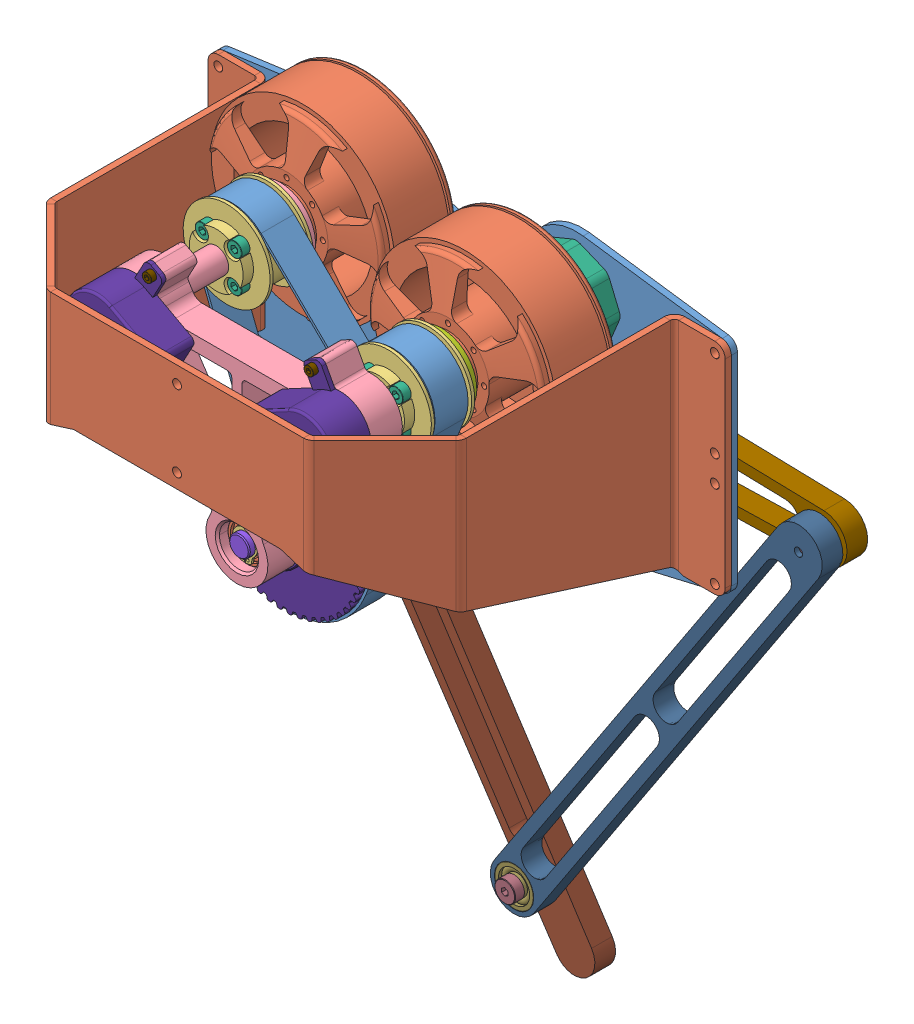
SolidWorks assembly Assembly, configuration Default. Lengths in mm.
Overall size (312.75 390.32 189.52).
164 component instances, 38 part files, 113 mates.
Components (placement in the parent):
- Mounting Plate-1: Mounting Plate [Default] at (803.8236 318.9692 0) size (250 143.05 3)
- Long Motor Assembly-1: Long Motor Assembly [Default] at (703.2032 181.8732 -91.3778) size (125.3 125.3 113)
  - T-Motor U10 KV80-1: T-Motor U10 KV80 [Default] at (50.6204 137.0959 94.3778) x (0.707107 -0.707107 0) z (0 0 1) size (88.6 88.6 43)
  - Timing Belt Pulley-1: Timing Belt Pulley [Default] at (50.6204 137.0959 142.3778) x (-0.707107 0.707107 0) z (0 0 -1) size (42 42 26)
  - Motor Shaft Long-1: Motor Shaft Long [Default] at (50.6204 137.0959 137.3778) x (0 -1 0) z (0 0 1) size (34 34 90)
  - ISO 10642 - M4 x 12 - 12C-9: ISO 10642 - M4 x 12 - 12C [ISO 10642 - M4 x 12 - 12C] at (50.6204 148.5959 142.3578) x (0 0 -1) z (0.997572 0.069644 0) size (12 7.53 7.53)
  - ISO 10642 - M4 x 12 - 12C-10: ISO 10642 - M4 x 12 - 12C [ISO 10642 - M4 x 12 - 12C] at (62.1204 137.0959 142.3578) x (0 0 -1) z (1 0 0) size (12 7.53 7.53)
  - ISO 10642 - M4 x 12 - 12C-11: ISO 10642 - M4 x 12 - 12C [ISO 10642 - M4 x 12 - 12C] at (39.1204 137.0959 142.3578) x (0 0 -1) z (1 0 0) size (12 7.53 7.53)
  - ISO 10642 - M4 x 12 - 12C-12: ISO 10642 - M4 x 12 - 12C [ISO 10642 - M4 x 12 - 12C] at (50.6204 125.5959 142.3578) x (0 0 -1) z (1 0 0) size (12 7.53 7.53)
  - ISO 4762 M4 x 25 - 25C-2: ISO 4762 M4 x 25 - 25C [PreviewCfg] at (58.3986 144.8741 167.3778) x (0 0 -1) z (1 0 0) size (29 7 7)
  - ISO 4762 M4 x 25 - 25C-4: ISO 4762 M4 x 25 - 25C [ISO 4762 M4 x 25 - 25C] at (42.8422 144.8741 167.3778) x (0 0 -1) z (0.999681 -0.025261 0) size (29 7 7)
  - ISO 4762 M4 x 25 - 25C-6: ISO 4762 M4 x 25 - 25C [ISO 4762 M4 x 25 - 25C] at (42.8422 129.3178 167.3778) x (0 0 -1) z (1 0 0) size (29 7 7)
  - ISO 4762 M4 x 25 - 25C-8: ISO 4762 M4 x 25 - 25C [ISO 4762 M4 x 25 - 25C] at (58.3986 129.3178 167.3778) x (0 0 -1) z (1 0 0) size (29 7 7)
- Short Motor Assembly-1: Short Motor Assembly [Default] at (703.2032 181.8732 -91.3778) size (125.3 125.3 91)
  - T-Motor U10 KV80-1: T-Motor U10 KV80 [Default] at (150.6204 137.0959 116.3778) x (0.707107 0.707107 0) z (0 0 1) size (88.6 88.6 43)
  - Timing Belt Pulley-1: Timing Belt Pulley [Default] at (150.6204 137.0959 164.3778) x (0.707107 0.707107 0) z (0 0 -1) size (42 42 26)
  - Motor Shaft Short-1: Motor Shaft Short [Default] at (150.6204 137.0959 159.3778) x (0 1 0) z (0 0 1) size (34 34 68)
  - ISO 10642 - M4 x 12 - 12C-9: ISO 10642 - M4 x 12 - 12C [ISO 10642 - M4 x 12 - 12C] at (139.1204 137.0959 164.3578) x (0 0 -1) z (1 -0.000264 0) size (12 7.53 7.53)
  - ISO 10642 - M4 x 12 - 12C-10: ISO 10642 - M4 x 12 - 12C [ISO 10642 - M4 x 12 - 12C] at (150.6204 148.5959 164.3578) x (0 0 -1) z (1 0 0) size (12 7.53 7.53)
  - ISO 10642 - M4 x 12 - 12C-11: ISO 10642 - M4 x 12 - 12C [ISO 10642 - M4 x 12 - 12C] at (162.1204 137.0959 164.3578) x (0 0 -1) z (1 0 0) size (12 7.53 7.53)
  - ISO 4762 M4 x 25 - 25C-2: ISO 4762 M4 x 25 - 25C [PreviewCfg] at (142.8422 144.8741 189.3778) x (0 0 -1) z (1 0 0) size (29 7 7)
  - ISO 4762 M4 x 25 - 25C-4: ISO 4762 M4 x 25 - 25C [ISO 4762 M4 x 25 - 25C] at (158.3986 129.3178 189.3778) x (0 0 -1) z (1 0 0) size (29 7 7)
  - ISO 4762 M4 x 25 - 25C-6: ISO 4762 M4 x 25 - 25C [ISO 4762 M4 x 25 - 25C] at (158.3986 144.8741 189.3778) x (0 0 -1) z (1 0 0) size (29 7 7)
  - ISO 10642 - M4 x 12 - 12C-12: ISO 10642 - M4 x 12 - 12C [ISO 10642 - M4 x 12 - 12C] at (150.6204 125.5959 164.3578) x (0 0 -1) z (1 0 0) size (12 7.53 7.53)
  - ISO 4762 M4 x 25 - 25C-8: ISO 4762 M4 x 25 - 25C [ISO 4762 M4 x 25 - 25C] at (142.8422 129.3178 189.3778) x (0 0 -1) z (1 0 0) size (29 7 7)
- Coaxial Shaft Assembly-1: Coaxial Shaft Assembly [Default] at (709.5255 181.8732 -91.3778) size (109.28 109.28 155)
  - Inner Shaft-1: Inner Shaft [Default] at (94.2981 61.5422 207.3778) x (0 0 -1) z (1 0 0) size (155 12 12)
  - Outer Shaft-1: Outer Shaft [Default] at (94.2981 61.5422 163.3778) x (0 0 -1) z (-1 0 0) size (100.5 20 20)
  - Flange-1: Flange [Default] at (94.2981 61.5422 94.3778) x (-0.866025 0.5 0) z (0 0 1) size (80 80 40)
  - SKF - 61804 - 18,SI,NC,18_68-5: SKF - 61804 - 18,SI,NC,18_68 [SKF - 61804 - 18,SI,NC,18_68] at (94.2981 61.5422 97.8778) x (0 0 1) z (-0.071685 -0.997427 0) size (7 32 32)
  - SKF - 61804 - 18,SI,NC,18_68-6: SKF - 61804 - 18,SI,NC,18_68 [SKF - 61804 - 18,SI,NC,18_68] at (94.2981 61.5422 130.8778) x (0 0 1) z (-1 0 0) size (7 32 32)
  - Circlip DIN 471 - 20 x 1.2-3: Circlip DIN 471 - 20 x 1.2 [Circlip DIN 471 - 20 x 1.2] at (94.2981 61.5422 93.0778) x (-1 0 0) z (0 0 -1) size (22.81 25.6 1.2)
  - HK_1210-1: HK_1210 [Default] at (94.2981 61.5422 163.3778) x (0 0 -1) z (1 0 0) size (10 16 16)
    - _HK_1210_PART1_2-1: _HK_1210_PART1_2 [Default] at origin size (10 16 16)
    - _HK_1210_PART2_4-1: _HK_1210_PART2_4 [Default] at origin size (6.3 1.5 1.5)
    - _HK_1210_PART2_4-2: _HK_1210_PART2_4 [Default] x (1 0 0) z (0 0.34202 0.939693) size (6.3 1.5 1.5)
    - _HK_1210_PART2_4-3: _HK_1210_PART2_4 [Default] x (1 0 0) z (0 0.642788 0.766044) size (6.3 1.5 1.5)
    - _HK_1210_PART2_4-4: _HK_1210_PART2_4 [Default] x (1 0 0) z (0 0.866025 0.5) size (6.3 1.5 1.5)
    - _HK_1210_PART2_4-5: _HK_1210_PART2_4 [Default] x (1 0 0) z (0 0.984808 0.173648) size (6.3 1.5 1.5)
    - _HK_1210_PART2_4-6: _HK_1210_PART2_4 [Default] x (1 0 0) z (0 0.984808 -0.173648) size (6.3 1.5 1.5)
    - _HK_1210_PART2_4-7: _HK_1210_PART2_4 [Default] x (1 0 0) z (0 0.866025 -0.5) size (6.3 1.5 1.5)
    - _HK_1210_PART2_4-8: _HK_1210_PART2_4 [Default] x (1 0 0) z (0 0.642788 -0.766044) size (6.3 1.5 1.5)
    - _HK_1210_PART2_4-9: _HK_1210_PART2_4 [Default] x (1 0 0) z (0 0.34202 -0.939693) size (6.3 1.5 1.5)
    - _HK_1210_PART2_4-10: _HK_1210_PART2_4 [Default] x (1 0 0) z (0 0 -1) size (6.3 1.5 1.5)
    - _HK_1210_PART2_4-11: _HK_1210_PART2_4 [Default] x (1 0 0) z (0 -0.34202 -0.939693) size (6.3 1.5 1.5)
    - _HK_1210_PART2_4-12: _HK_1210_PART2_4 [Default] x (1 0 0) z (0 -0.642788 -0.766044) size (6.3 1.5 1.5)
    - _HK_1210_PART2_4-13: _HK_1210_PART2_4 [Default] x (1 0 0) z (0 -0.866025 -0.5) size (6.3 1.5 1.5)
    - _HK_1210_PART2_4-14: _HK_1210_PART2_4 [Default] x (1 0 0) z (0 -0.984808 -0.173648) size (6.3 1.5 1.5)
    - _HK_1210_PART2_4-15: _HK_1210_PART2_4 [Default] x (1 0 0) z (0 -0.984808 0.173648) size (6.3 1.5 1.5)
    - _HK_1210_PART2_4-16: _HK_1210_PART2_4 [Default] x (1 0 0) z (0 -0.866025 0.5) size (6.3 1.5 1.5)
    - _HK_1210_PART2_4-17: _HK_1210_PART2_4 [Default] x (1 0 0) z (0 -0.642788 0.766044) size (6.3 1.5 1.5)
    - _HK_1210_PART2_4-18: _HK_1210_PART2_4 [Default] x (1 0 0) z (0 -0.34202 0.939693) size (6.3 1.5 1.5)
    - _HK_1210_PART3_23-1: _HK_1210_PART3_23 [Default] at origin size (6.3 1.5 1.5)
    - _HK_1210_PART3_23-2: _HK_1210_PART3_23 [Default] x (1 0 0) z (0 0.34202 0.939693) size (6.3 1.5 1.5)
    - _HK_1210_PART3_23-3: _HK_1210_PART3_23 [Default] x (1 0 0) z (0 0.642788 0.766044) size (6.3 1.5 1.5)
    - _HK_1210_PART3_23-4: _HK_1210_PART3_23 [Default] x (1 0 0) z (0 0.866025 0.5) size (6.3 1.5 1.5)
    - _HK_1210_PART3_23-5: _HK_1210_PART3_23 [Default] x (1 0 0) z (0 0.984808 0.173648) size (6.3 1.5 1.5)
    - _HK_1210_PART3_23-6: _HK_1210_PART3_23 [Default] x (1 0 0) z (0 0.984808 -0.173648) size (6.3 1.5 1.5)
    - _HK_1210_PART3_23-7: _HK_1210_PART3_23 [Default] x (1 0 0) z (0 0.866025 -0.5) size (6.3 1.5 1.5)
    - _HK_1210_PART3_23-8: _HK_1210_PART3_23 [Default] x (1 0 0) z (0 0.642788 -0.766044) size (6.3 1.5 1.5)
    - _HK_1210_PART3_23-9: _HK_1210_PART3_23 [Default] x (1 0 0) z (0 0.34202 -0.939693) size (6.3 1.5 1.5)
    - _HK_1210_PART3_23-10: _HK_1210_PART3_23 [Default] x (1 0 0) z (0 0 -1) size (6.3 1.5 1.5)
    - _HK_1210_PART3_23-11: _HK_1210_PART3_23 [Default] x (1 0 0) z (0 -0.34202 -0.939693) size (6.3 1.5 1.5)
    - _HK_1210_PART3_23-12: _HK_1210_PART3_23 [Default] x (1 0 0) z (0 -0.642788 -0.766044) size (6.3 1.5 1.5)
    - _HK_1210_PART3_23-13: _HK_1210_PART3_23 [Default] x (1 0 0) z (0 -0.866025 -0.5) size (6.3 1.5 1.5)
    - _HK_1210_PART3_23-14: _HK_1210_PART3_23 [Default] x (1 0 0) z (0 -0.984808 -0.173648) size (6.3 1.5 1.5)
    - _HK_1210_PART3_23-15: _HK_1210_PART3_23 [Default] x (1 0 0) z (0 -0.984808 0.173648) size (6.3 1.5 1.5)
    - _HK_1210_PART3_23-16: _HK_1210_PART3_23 [Default] x (1 0 0) z (0 -0.866025 0.5) size (6.3 1.5 1.5)
    - _HK_1210_PART3_23-17: _HK_1210_PART3_23 [Default] x (1 0 0) z (0 -0.642788 0.766044) size (6.3 1.5 1.5)
    - _HK_1210_PART3_23-18: _HK_1210_PART3_23 [Default] x (1 0 0) z (0 -0.34202 0.939693) size (6.3 1.5 1.5)
  - HK_1210-2: HK_1210 [Default] at (94.2981 61.5422 72.8778) x (0 0 -1) z (1 0 0) size (10 16 16)
    - _HK_1210_PART1_2-1: _HK_1210_PART1_2 [Default] at origin size (10 16 16)
    - _HK_1210_PART2_4-1: _HK_1210_PART2_4 [Default] at origin size (6.3 1.5 1.5)
    - _HK_1210_PART2_4-2: _HK_1210_PART2_4 [Default] x (1 0 0) z (0 0.34202 0.939693) size (6.3 1.5 1.5)
    - _HK_1210_PART2_4-3: _HK_1210_PART2_4 [Default] x (1 0 0) z (0 0.642788 0.766044) size (6.3 1.5 1.5)
    - _HK_1210_PART2_4-4: _HK_1210_PART2_4 [Default] x (1 0 0) z (0 0.866025 0.5) size (6.3 1.5 1.5)
    - _HK_1210_PART2_4-5: _HK_1210_PART2_4 [Default] x (1 0 0) z (0 0.984808 0.173648) size (6.3 1.5 1.5)
    - _HK_1210_PART2_4-6: _HK_1210_PART2_4 [Default] x (1 0 0) z (0 0.984808 -0.173648) size (6.3 1.5 1.5)
    - _HK_1210_PART2_4-7: _HK_1210_PART2_4 [Default] x (1 0 0) z (0 0.866025 -0.5) size (6.3 1.5 1.5)
    - _HK_1210_PART2_4-8: _HK_1210_PART2_4 [Default] x (1 0 0) z (0 0.642788 -0.766044) size (6.3 1.5 1.5)
    - _HK_1210_PART2_4-9: _HK_1210_PART2_4 [Default] x (1 0 0) z (0 0.34202 -0.939693) size (6.3 1.5 1.5)
    - _HK_1210_PART2_4-10: _HK_1210_PART2_4 [Default] x (1 0 0) z (0 0 -1) size (6.3 1.5 1.5)
    - _HK_1210_PART2_4-11: _HK_1210_PART2_4 [Default] x (1 0 0) z (0 -0.34202 -0.939693) size (6.3 1.5 1.5)
    - _HK_1210_PART2_4-12: _HK_1210_PART2_4 [Default] x (1 0 0) z (0 -0.642788 -0.766044) size (6.3 1.5 1.5)
    - _HK_1210_PART2_4-13: _HK_1210_PART2_4 [Default] x (1 0 0) z (0 -0.866025 -0.5) size (6.3 1.5 1.5)
    - _HK_1210_PART2_4-14: _HK_1210_PART2_4 [Default] x (1 0 0) z (0 -0.984808 -0.173648) size (6.3 1.5 1.5)
    - _HK_1210_PART2_4-15: _HK_1210_PART2_4 [Default] x (1 0 0) z (0 -0.984808 0.173648) size (6.3 1.5 1.5)
    - _HK_1210_PART2_4-16: _HK_1210_PART2_4 [Default] x (1 0 0) z (0 -0.866025 0.5) size (6.3 1.5 1.5)
    - _HK_1210_PART2_4-17: _HK_1210_PART2_4 [Default] x (1 0 0) z (0 -0.642788 0.766044) size (6.3 1.5 1.5)
    - _HK_1210_PART2_4-18: _HK_1210_PART2_4 [Default] x (1 0 0) z (0 -0.34202 0.939693) size (6.3 1.5 1.5)
    - _HK_1210_PART3_23-1: _HK_1210_PART3_23 [Default] at origin size (6.3 1.5 1.5)
    - _HK_1210_PART3_23-2: _HK_1210_PART3_23 [Default] x (1 0 0) z (0 0.34202 0.939693) size (6.3 1.5 1.5)
    - _HK_1210_PART3_23-3: _HK_1210_PART3_23 [Default] x (1 0 0) z (0 0.642788 0.766044) size (6.3 1.5 1.5)
    - _HK_1210_PART3_23-4: _HK_1210_PART3_23 [Default] x (1 0 0) z (0 0.866025 0.5) size (6.3 1.5 1.5)
    - _HK_1210_PART3_23-5: _HK_1210_PART3_23 [Default] x (1 0 0) z (0 0.984808 0.173648) size (6.3 1.5 1.5)
    - _HK_1210_PART3_23-6: _HK_1210_PART3_23 [Default] x (1 0 0) z (0 0.984808 -0.173648) size (6.3 1.5 1.5)
    - _HK_1210_PART3_23-7: _HK_1210_PART3_23 [Default] x (1 0 0) z (0 0.866025 -0.5) size (6.3 1.5 1.5)
    - _HK_1210_PART3_23-8: _HK_1210_PART3_23 [Default] x (1 0 0) z (0 0.642788 -0.766044) size (6.3 1.5 1.5)
    - _HK_1210_PART3_23-9: _HK_1210_PART3_23 [Default] x (1 0 0) z (0 0.34202 -0.939693) size (6.3 1.5 1.5)
    - _HK_1210_PART3_23-10: _HK_1210_PART3_23 [Default] x (1 0 0) z (0 0 -1) size (6.3 1.5 1.5)
    - _HK_1210_PART3_23-11: _HK_1210_PART3_23 [Default] x (1 0 0) z (0 -0.34202 -0.939693) size (6.3 1.5 1.5)
    - _HK_1210_PART3_23-12: _HK_1210_PART3_23 [Default] x (1 0 0) z (0 -0.642788 -0.766044) size (6.3 1.5 1.5)
    - _HK_1210_PART3_23-13: _HK_1210_PART3_23 [Default] x (1 0 0) z (0 -0.866025 -0.5) size (6.3 1.5 1.5)
    - _HK_1210_PART3_23-14: _HK_1210_PART3_23 [Default] x (1 0 0) z (0 -0.984808 -0.173648) size (6.3 1.5 1.5)
    - _HK_1210_PART3_23-15: _HK_1210_PART3_23 [Default] x (1 0 0) z (0 -0.984808 0.173648) size (6.3 1.5 1.5)
    - _HK_1210_PART3_23-16: _HK_1210_PART3_23 [Default] x (1 0 0) z (0 -0.866025 0.5) size (6.3 1.5 1.5)
    - _HK_1210_PART3_23-17: _HK_1210_PART3_23 [Default] x (1 0 0) z (0 -0.642788 0.766044) size (6.3 1.5 1.5)
    - _HK_1210_PART3_23-18: _HK_1210_PART3_23 [Default] x (1 0 0) z (0 -0.34202 0.939693) size (6.3 1.5 1.5)
  - Outer Timing Belt Gear-1: Outer Timing Belt Gear [Default] at (94.2981 61.5422 163.3778) x (1 0 0) z (0 0 -1) size (76.29 76.29 29)
  - Inner Timing Belt Gear-1: Inner Timing Belt Gear [Default] at (94.2981 61.5422 164.3778) size (76.29 76.29 28)
  - ISO 8734 - 4 x 32 - A - St-3: ISO 8734 - 4 x 32 - A - St [ISO 8734 - 4 x 32 - A - St] at (94.2981 45.5422 188.8778) x (0 1 0) z (0.480016 0 0.87726) size (32 4 4)
  - ISO 4762 M3 x 12 - 12C-3: ISO 4762 M3 x 12 - 12C [ISO 4762 M3 x 12 - 12C] at (94.2981 39.5422 138.8778) x (0 1 0) z (0.922632 0 -0.385681) size (15 5.5 5.5)
  - ISO 4762 M3 x 12 - 12C-4: ISO 4762 M3 x 12 - 12C [ISO 4762 M3 x 12 - 12C] at (94.2981 83.5422 138.8778) x (0 -1 0) z (0.974179 0 0.225776) size (15 5.5 5.5)
- SKF - 61800 - 14,SI,NC,14_68-5: SKF - 61800 - 14,SI,NC,14_68 [SKF - 61800 - 14,SI,NC,14_68] at (803.8236 243.4155 109.5) x (0 0 1) z (-0.331189 0.943564 0) size (5 19 19)
- Circlip DIN 471 - 10 x 1-8: Circlip DIN 471 - 10 x 1 [Circlip DIN 471 - 10 x 1] at (803.8236 243.4155 113.1) size (12.16 14.7 1)
- Support Brace-1: Support Brace [Default] at (803.8236 318.9692 109.5) x (-1 0 0) z (0 0 -1) size (131.26 114.86 15)
- SKF - 61800 - 14,SI,NC,14_68-6: SKF - 61800 - 14,SI,NC,14_68 [SKF - 61800 - 14,SI,NC,14_68] at (753.8236 318.9692 109.5) x (0 0 -1) z (-0.924864 0.380297 0) size (5 19 19)
- SKF - 61800 - 14,SI,NC,14_68-7: SKF - 61800 - 14,SI,NC,14_68 [SKF - 61800 - 14,SI,NC,14_68] at (853.8236 318.9692 109.5) x (0 0 -1) z (-0.072342 0.99738 0) size (5 19 19)
- Circlip DIN 471 - 10 x 1-9: Circlip DIN 471 - 10 x 1 [Circlip DIN 471 - 10 x 1] at (753.8236 318.9692 113.1) x (0.999962 0.008683 0) z (0 0 1) size (12.16 14.7 1)
- Circlip DIN 471 - 10 x 1-10: Circlip DIN 471 - 10 x 1 [Circlip DIN 471 - 10 x 1] at (853.8236 318.9692 113.1) x (0.996379 0.085026 0) z (0 0 1) size (12.16 14.7 1)
- ISO 4762 M4 x 8 - 8C-38: ISO 4762 M4 x 8 - 8C [ISO 4762 M4 x 8 - 8C] at (753.8236 334.9692 -4) x (0 0 1) z (-1 0 0) size (12 7 7)
- ISO 4762 M4 x 8 - 8C-39: ISO 4762 M4 x 8 - 8C [ISO 4762 M4 x 8 - 8C] at (769.8236 318.9692 -4) x (0 0 1) z (-1 0 0) size (12 7 7)
- ISO 4762 M4 x 8 - 8C-40: ISO 4762 M4 x 8 - 8C [ISO 4762 M4 x 8 - 8C] at (753.8236 302.9692 -4) x (0 0 1) z (-1 0 0) size (12 7 7)
- ISO 4762 M4 x 8 - 8C-41: ISO 4762 M4 x 8 - 8C [ISO 4762 M4 x 8 - 8C] at (737.8236 318.9692 -4) x (0 0 1) z (-1 0 0) size (12 7 7)
- Motor Mounting-1: Motor Mounting [Default] at (853.8236 318.9692 3) size (42.47 42.47 22)
- ISO 4762 M4 x 30 - 20C-40: ISO 4762 M4 x 30 - 20C [ISO 4762 M4 x 30 - 20C] at (853.8236 334.9692 -4) x (0 0 1) z (-1 0 0) size (34 7 7)
- ISO 4762 M4 x 30 - 20C-41: ISO 4762 M4 x 30 - 20C [ISO 4762 M4 x 30 - 20C] at (869.8236 318.9692 -4) x (0 0 1) z (-1 0 0) size (34 7 7)
- ISO 4762 M4 x 30 - 20C-42: ISO 4762 M4 x 30 - 20C [ISO 4762 M4 x 30 - 20C] at (853.8236 302.9692 -4) x (0 0 1) z (-1 0 0) size (34 7 7)
- ISO 4762 M4 x 30 - 20C-43: ISO 4762 M4 x 30 - 20C [ISO 4762 M4 x 30 - 20C] at (837.8236 318.9692 -4) x (0 0 1) z (-1 0 0) size (34 7 7)
- ISO 4762 M4 x 8 - 8C-42: ISO 4762 M4 x 8 - 8C [ISO 4762 M4 x 8 - 8C] at (803.8236 275.9155 -4) x (0 0 1) z (-1 0 0) size (12 7 7)
- ISO 4762 M4 x 8 - 8C-43: ISO 4762 M4 x 8 - 8C [ISO 4762 M4 x 8 - 8C] at (775.6778 259.6655 -4) x (0 0 1) z (-1 0 0) size (12 7 7)
- ISO 4762 M4 x 8 - 8C-44: ISO 4762 M4 x 8 - 8C [ISO 4762 M4 x 8 - 8C] at (775.6778 227.1655 -4) x (0 0 1) z (-1 0 0) size (12 7 7)
- ISO 4762 M4 x 8 - 8C-45: ISO 4762 M4 x 8 - 8C [ISO 4762 M4 x 8 - 8C] at (831.9694 259.6655 -4) x (0 0 1) z (-1 0 0) size (12 7 7)
- ISO 4762 M4 x 8 - 8C-46: ISO 4762 M4 x 8 - 8C [ISO 4762 M4 x 8 - 8C] at (831.9694 227.1655 -4) x (0 0 1) z (-1 0 0) size (12 7 7)
- ISO 4762 M4 x 8 - 8C-47: ISO 4762 M4 x 8 - 8C [ISO 4762 M4 x 8 - 8C] at (803.8236 210.9155 -4) x (0 0 1) z (-1 0 0) size (12 7 7)
- Leg Assembly-2: Leg Assembly [Default] at (881.8415 93.4592 582.2565) x (-0.999747 -0.022471 0) z (0 0 -1) size (306.78 269.08 31)
  - Outer Short Link-1: Outer Short Link [Default] at (74.6286 151.6715 599.2565) x (-0.022471 0.999747 0) z (0.999747 0.022471 0) size (34 10 164)
  - Inner Short Link-1: Inner Short Link [Default] at (74.6286 151.6715 611.2565) x (0.022471 -0.999747 0) z (-0.999747 -0.022471 0) size (33.99 10 164)
  - Long Link-1: Long Link [Default] at (-62.8367 148.5818 609.2565) x (0.568628 -0.822595 0) z (0.822595 0.568628 0) size (273 10 23)
  - Extra Long Link-1: Extra Long Link [Default] at (212.0939 154.7613 621.2565) x (-0.531094 -0.847313 0) z (0.847313 -0.531094 0) size (301.49 10 23)
  - SKF - 626 - 8,SI,NC,8_68-8: SKF - 626 - 8,SI,NC,8_68 [SKF - 626 - 8,SI,NC,8_68] at (212.0939 154.7613 602.2565) x (0 0 -1) z (0.999791 0.020442 0) size (6 19 19)
  - ISO 7379 - 6 x 10 --- C-7: ISO 7379 - 6 x 10 --- C [ISO 7379 - 6 x 10 --- C] at (212.0939 154.7613 594.7565) x (0 0 1) z (0.999947 -0.010306 0) size (24.25 10 10)
  - Leg Spacer-1: Leg Spacer [Default] at (212.0939 154.7613 611.2565) x (-0.080045 0.996791 0) z (-0.996791 -0.080045 0) size (8.2 6 8.2)
  - SKF - 626 - 8,SI,NC,8_68-9: SKF - 626 - 8,SI,NC,8_68 [SKF - 626 - 8,SI,NC,8_68] at (-62.8367 148.5818 618.2565) x (0 0 1) z (-1 0 0) size (6 19 19)
  - SKF - 626 - 8,SI,NC,8_68-10: SKF - 626 - 8,SI,NC,8_68 [SKF - 626 - 8,SI,NC,8_68] at (79.3203 -57.0669 602.2565) x (0 0 -1) z (1 0 0) size (6 19 19)
  - ISO 7379 - 6 x 10 --- C-8: ISO 7379 - 6 x 10 --- C [ISO 7379 - 6 x 10 --- C] at (79.3203 -57.0669 594.7565) x (0 0 1) z (-1 0 0) size (24.25 10 10)
  - Leg Spacer-2: Leg Spacer [Default] at (79.3203 -57.0669 605.2565) x (0.117154 0.993114 0) z (0.993114 -0.117154 0) size (8.2 6 8.2)
  - ISO 7379 - 6 x 10 --- C-9: ISO 7379 - 6 x 10 --- C [ISO 7379 - 6 x 10 --- C] at (-62.8367 148.5818 625.7565) x (0 0 -1) z (1 0 0) size (24.25 10 10)
  - Leg Spacer-3: Leg Spacer [Default] at (-62.8367 148.5818 609.2565) x (0.995138 0.09849 0) z (0.09849 -0.995138 0) size (8.2 6 8.2)
- ISO 4029 - M4 x 8-C-9: ISO 4029 - M4 x 8-C [ISO 4029 - M4 x 8-C] at (803.8236 229.4994 -34) x (0 1 0) z (-0.347527 0 -0.93767) size (8 4 4)
- ISO 4029 - M4 x 8-C-10: ISO 4029 - M4 x 8-C [ISO 4029 - M4 x 8-C] at (803.8236 225.4656 -22) x (0 1 0) z (-0.06505 0 -0.997882) size (8 4 4)
- ISO 4029 - M4 x 8-C-11: ISO 4029 - M4 x 8-C [ISO 4029 - M4 x 8-C] at (803.8236 257.3315 -34) x (0 -1 0) z (0.502893 0 -0.864349) size (8 4 4)
- ISO 4029 - M4 x 8-C-12: ISO 4029 - M4 x 8-C [ISO 4029 - M4 x 8-C] at (803.8236 261.3653 -22) x (0 -1 0) z (-0.029243 0 -0.999572) size (8 4 4)
- Encoder Shaft-1: Encoder Shaft [Default] at (853.8236 318.9692 113) x (-0.51827 -0.855217 0) z (-0.855217 0.51827 0) size (12.1 18 12.1)
- Encoder Shaft-2: Encoder Shaft [Default] at (753.8236 318.9692 113) x (0.667835 -0.744309 0) z (-0.744309 -0.667835 0) size (12.1 18 12.1)
- HEDL-5640-A13 Encoder-1: HEDL-5640-A13 Encoder [Default] at (753.8236 318.9692 117) x (0.473352 0.880874 0) z (0.880874 -0.473352 0) size (52.1 18.3 41.1)
- HEDL-5640-A13 Encoder-2: HEDL-5640-A13 Encoder [Default] at (853.8236 318.9692 117) x (0.473352 -0.880874 0) z (-0.880874 -0.473352 0) size (52.1 18.3 41.1)
- ISO 4762 M2.5 x 12 - 12C-6: ISO 4762 M2.5 x 12 - 12C [ISO 4762 M2.5 x 12 - 12C] at (764.7107 339.2292 121.5) x (0 0 -1) z (1 0 0) size (14.5 4.5 4.5)
- ISO 4762 M2.5 x 12 - 12C-7: ISO 4762 M2.5 x 12 - 12C [ISO 4762 M2.5 x 12 - 12C] at (742.9365 298.7091 121.5) x (0 0 -1) z (1 0 0) size (14.5 4.5 4.5)
- ISO 4762 M2.5 x 12 - 12C-8: ISO 4762 M2.5 x 12 - 12C [ISO 4762 M2.5 x 12 - 12C] at (842.9365 339.2292 121.5) x (0 0 -1) z (1 0 0) size (14.5 4.5 4.5)
- ISO 4762 M2.5 x 12 - 12C-9: ISO 4762 M2.5 x 12 - 12C [ISO 4762 M2.5 x 12 - 12C] at (864.7107 298.7091 121.5) x (0 0 -1) z (1 0 0) size (14.5 4.5 4.5)
- Contitech T5 365mm Timing Belt-1: Contitech T5 365mm Timing Belt [Default] at (803.8236 243.4155 69.5) x (0 0 -1) z (0.833926 0.551876 0) size (16 150.29 78.79)
- Contitech T5 365mm Timing Belt-2: Contitech T5 365mm Timing Belt [Default] at (803.8236 243.4155 91.5) x (0 0 -1) z (0.833926 -0.551876 0) size (16 150.29 78.79)
- hopper-boom-attachment-3: hopper-boom-attachment [Default] at (703.3258 228.528 -20) x (0 0 1) z (0 -1 0) size (143.02 250.07 106)
Mates (geometry in assembly coordinates):
- Concentric459: concentric: cylinder of Support Brace-1 through (50.6204 137.0959 233.0282) axis (0 0 -1) radius 10; cylinder of ? through (50.6204 137.0959 226.5991) axis (0 0 -1) radius 10
- Concentric4601: concentric: cylinder of Support Brace-1 through (50.6204 137.0959 203.2778) axis (0 0 -1) radius 10; cylinder of ? through (50.6204 137.0959 205.3778) axis (0 0 1) radius 10
- Coincident3141: coincident: plane of Support Brace-1 through (50.6204 147.0959 206.3778) normal (0 0 -1); plane of ? through (50.6204 137.0959 206.3778) normal (0 0 1)
- Concentric465: concentric: cylinder of Support Brace-1 through (150.6204 137.0959 203.2778) axis (0 0 -1) radius 9.5; cylinder of ? through (150.6204 137.0959 205.3778) axis (0 0 1) radius 10
- Coincident319: coincident: plane of Support Brace-1 through (150.6204 147.0959 206.3778) normal (0 0 -1); plane of ? through (150.6204 137.0959 206.3778) normal (0 0 1)
- Concentric470: concentric: cylinder of Support Brace-1 through (100.6204 57.0959 203.2778) axis (0 0 -1) radius 10; cylinder of ? through (100.6204 57.0959 205.3778) axis (0 0 1) radius 10
- Coincident324: coincident: plane of Support Brace-1 through (100.6204 47.0959 206.3778) normal (0 0 -1); plane of ? through (100.6204 57.0959 206.3778) normal (0 0 1)
- Concentric4602: concentric: cylinder of Support Brace-1 through (753.8236 318.9692 102) axis (0 0 -1) radius 9.5; cylinder of SKF - 61800 - 14,SI,NC,14_68-6 through (753.8236 318.9692 130.1375) axis (0 0 -1) radius 9.5
- Coincident3142: coincident: plane of Support Brace-1 through (753.8236 326.4692 107) normal (0 0 1); plane of SKF - 61800 - 14,SI,NC,14_68-6 through (750.3248 310.4604 107) normal (0 0 -1)
- Concentric4622: concentric: cylinder of Mounting Plate-1 through (753.8236 334.9692 3) axis (0 0 1) radius 2; cylinder of ISO 4762 M4 x 8 - 8C-38 through (753.8236 334.9692 -35.75) axis (0 0 -1) radius 3.5
- Coincident3149: coincident: plane of Mounting Plate-1 through (853.8236 318.9692 0) normal (0 0 -1); plane of ISO 4762 M4 x 8 - 8C-38 through (753.8236 338.4692 0) normal (0 0 1)
- Concentric46231: concentric: cylinder of Mounting Plate-1 through (769.8236 318.9692 3) axis (0 0 1) radius 2; cylinder of ISO 4762 M4 x 8 - 8C-39 through (769.8236 318.9692 -35.75) axis (0 0 -1) radius 3.5
- Coincident31501: coincident: plane of Mounting Plate-1 through (853.8236 318.9692 0) normal (0 0 -1); plane of ISO 4762 M4 x 8 - 8C-39 through (769.8236 322.4692 0) normal (0 0 1)
- Concentric46241: concentric: cylinder of Mounting Plate-1 through (753.8236 302.9692 3) axis (0 0 1) radius 2; cylinder of ISO 4762 M4 x 8 - 8C-40 through (753.8236 302.9692 -35.75) axis (0 0 -1) radius 3.5
- Coincident31511: coincident: plane of Mounting Plate-1 through (853.8236 318.9692 0) normal (0 0 -1); plane of ISO 4762 M4 x 8 - 8C-40 through (753.8236 306.4692 0) normal (0 0 1)
- Concentric46251: concentric: cylinder of Mounting Plate-1 through (737.8236 318.9692 3) axis (0 0 1) radius 2; cylinder of ISO 4762 M4 x 8 - 8C-41 through (737.8236 318.9692 -35.75) axis (0 0 -1) radius 3.5
- Coincident31521: coincident: plane of Mounting Plate-1 through (853.8236 318.9692 0) normal (0 0 -1); plane of ISO 4762 M4 x 8 - 8C-41 through (737.8236 322.4692 0) normal (0 0 1)
- Concentric46482: concentric: cylinder of Mounting Plate-1 through (869.8236 318.9692 3) axis (0 0 1) radius 2; cylinder of Motor Mounting-1 through (869.8236 318.9692 25) axis (0 0 1) radius 2.15
- Concentric46483: concentric: cylinder of Mounting Plate-1 through (853.8236 334.9692 3) axis (0 0 1) radius 2; cylinder of Motor Mounting-1 through (853.8236 334.9692 25) axis (0 0 1) radius 2.15
- Concentric46484: concentric: cylinder of Mounting Plate-1 through (853.8236 334.9692 3) axis (0 0 1) radius 2; cylinder of ISO 4762 M4 x 30 - 20C-40 through (853.8236 334.9692 -35.75) axis (0 0 -1) radius 3.5
- Coincident31754: coincident: plane of Mounting Plate-1 through (853.8236 318.9692 0) normal (0 0 -1); plane of ISO 4762 M4 x 30 - 20C-40 through (853.8236 338.4692 0) normal (0 0 1)
- Concentric464851: concentric: cylinder of Mounting Plate-1 through (869.8236 318.9692 3) axis (0 0 1) radius 2; cylinder of ISO 4762 M4 x 30 - 20C-41 through (869.8236 318.9692 -35.75) axis (0 0 -1) radius 3.5
- Coincident317551: coincident: plane of Mounting Plate-1 through (853.8236 318.9692 0) normal (0 0 -1); plane of ISO 4762 M4 x 30 - 20C-41 through (869.8236 322.4692 0) normal (0 0 1)
- Concentric464861: concentric: cylinder of Mounting Plate-1 through (853.8236 302.9692 3) axis (0 0 1) radius 2; cylinder of ISO 4762 M4 x 30 - 20C-42 through (853.8236 302.9692 -35.75) axis (0 0 -1) radius 3.5
- Coincident317561: coincident: plane of Mounting Plate-1 through (853.8236 318.9692 0) normal (0 0 -1); plane of ISO 4762 M4 x 30 - 20C-42 through (853.8236 306.4692 0) normal (0 0 1)
- Concentric464871: concentric: cylinder of Mounting Plate-1 through (837.8236 318.9692 3) axis (0 0 1) radius 2; cylinder of ISO 4762 M4 x 30 - 20C-43 through (837.8236 318.9692 -35.75) axis (0 0 -1) radius 3.5
- Coincident317571: coincident: plane of Mounting Plate-1 through (853.8236 318.9692 0) normal (0 0 -1); plane of ISO 4762 M4 x 30 - 20C-43 through (837.8236 322.4692 0) normal (0 0 1)
- Concentric464872: concentric: cylinder of Mounting Plate-1 through (803.8236 275.9155 3) axis (0 0 1) radius 2; cylinder of ISO 4762 M4 x 8 - 8C-42 through (803.8236 275.9155 -35.75) axis (0 0 -1) radius 3.5
- Coincident317572: coincident: plane of Mounting Plate-1 through (853.8236 318.9692 0) normal (0 0 -1); plane of ISO 4762 M4 x 8 - 8C-42 through (803.8236 279.4155 0) normal (0 0 1)
- Concentric4648731: concentric: cylinder of Mounting Plate-1 through (775.6778 259.6655 3) axis (0 0 1) radius 2; cylinder of ISO 4762 M4 x 8 - 8C-43 through (775.6778 259.6655 -35.75) axis (0 0 -1) radius 3.5
- Coincident3175731: coincident: plane of Mounting Plate-1 through (853.8236 318.9692 0) normal (0 0 -1); plane of ISO 4762 M4 x 8 - 8C-43 through (775.6778 263.1655 0) normal (0 0 1)
- Concentric4648741: concentric: cylinder of Mounting Plate-1 through (775.6778 227.1655 3) axis (0 0 1) radius 2; cylinder of ISO 4762 M4 x 8 - 8C-44 through (775.6778 227.1655 -35.75) axis (0 0 -1) radius 3.5
- Coincident3175741: coincident: plane of Mounting Plate-1 through (853.8236 318.9692 0) normal (0 0 -1); plane of ISO 4762 M4 x 8 - 8C-44 through (775.6778 230.6655 0) normal (0 0 1)
- Concentric4648751: concentric: cylinder of Mounting Plate-1 through (831.9694 259.6655 3) axis (0 0 1) radius 2; cylinder of ISO 4762 M4 x 8 - 8C-45 through (831.9694 259.6655 -35.75) axis (0 0 -1) radius 3.5
- Coincident3175751: coincident: plane of Mounting Plate-1 through (853.8236 318.9692 0) normal (0 0 -1); plane of ISO 4762 M4 x 8 - 8C-45 through (831.9694 263.1655 0) normal (0 0 1)
- Concentric4648761: concentric: cylinder of Mounting Plate-1 through (831.9694 227.1655 3) axis (0 0 1) radius 2; cylinder of ISO 4762 M4 x 8 - 8C-46 through (831.9694 227.1655 -35.75) axis (0 0 -1) radius 3.5
- Coincident3175761: coincident: plane of Mounting Plate-1 through (853.8236 318.9692 0) normal (0 0 -1); plane of ISO 4762 M4 x 8 - 8C-46 through (831.9694 230.6655 0) normal (0 0 1)
- Concentric4648771: concentric: cylinder of Mounting Plate-1 through (803.8236 210.9155 3) axis (0 0 1) radius 2; cylinder of ISO 4762 M4 x 8 - 8C-47 through (803.8236 210.9155 -35.75) axis (0 0 -1) radius 3.5
- Coincident3175771: coincident: plane of Mounting Plate-1 through (853.8236 318.9692 0) normal (0 0 -1); plane of ISO 4762 M4 x 8 - 8C-47 through (803.8236 214.4155 0) normal (0 0 1)
- Coincident3175773: coincident: plane of Mounting Plate-1 through (853.8236 318.9692 3) normal (0 0 1); plane of Coaxial Shaft Assembly-1/Flange-1 through (803.8236 243.4155 3) normal (0 0 -1)
- Concentric4648775: concentric: cylinder of Mounting Plate-1 through (803.8236 243.4155 3) axis (0 0 -1) radius 14.5; cylinder of Coaxial Shaft Assembly-1/Flange-1 through (803.8236 243.4155 59.3012) axis (0 0 1) radius 14.5
- Concentric4648776: concentric: cylinder of Mounting Plate-1 through (775.6778 259.6655 3) axis (0 0 1) radius 2; cylinder of Coaxial Shaft Assembly-1/Flange-1 through (775.6778 259.6655 3) axis (0 0 1) radius 1.5
- Coincident3175775: coincident: plane of Mounting Plate-1 through (853.8236 318.9692 3) normal (0 0 1); plane of Coaxial Shaft Assembly-1/SKF - 61804 - 18,SI,NC,18_68-5 through (789.6601 244.4334 3) normal (0 0 -1)
- Concentric469: concentric: cylinder of Coaxial Shaft Assembly-1/Inner Shaft-1 through (803.8236 243.4155 -39) axis (0 0 -1) radius 4.8; cylinder of Circlip DIN 471 - 10 x 1-8 through (803.8236 243.4155 112.1) axis (0 0 1) radius 4.8
- Coincident323: coincident: plane of Coaxial Shaft Assembly-1/Inner Shaft-1 through (803.8236 248.2155 113.1) normal (0 0 -1); plane of Circlip DIN 471 - 10 x 1-8 through (803.8236 243.4155 113.1) normal (0 0 1)
- Parallel7: parallel: plane of Circlip DIN 471 - 10 x 1-8 through (803.8236 243.4155 113.1) normal (1 0 0); plane of Coaxial Shaft Assembly-1 through (709.5255 181.8732 -91.3778) normal (1 0 0)
- Concentric468: concentric: cylinder of Coaxial Shaft Assembly-1/Inner Shaft-1 through (803.8236 243.4155 -39) axis (0 0 -1) radius 5; cylinder of SKF - 61800 - 14,SI,NC,14_68-5 through (803.8236 243.4155 88.8625) axis (0 0 1) radius 5
- Coincident322: coincident: plane of Coaxial Shaft Assembly-1/Inner Shaft-1 through (803.8236 249.4155 107) normal (0 0 1); plane of SKF - 61800 - 14,SI,NC,14_68-5 through (809.8152 245.5185 107) normal (0 0 -1)
- Coincident3175782: coincident: plane of Mounting Plate-1 through (853.8236 318.9692 3) normal (0 0 1); plane of Long Motor Assembly-1/T-Motor U10 KV80-1 through (753.8236 318.9692 3) normal (0 0 -1)
- Concentric4648790: concentric: cylinder of Long Motor Assembly-1/T-Motor U10 KV80-1 through (769.8236 318.9692 3) axis (0 0 -1) radius 1.65; cylinder of Mounting Plate-1 through (769.8236 318.9692 3) axis (0 0 1) radius 2
- Concentric4648791: concentric: cylinder of Mounting Plate-1 through (753.8236 334.9692 3) axis (0 0 1) radius 2; cylinder of Long Motor Assembly-1/T-Motor U10 KV80-1 through (753.8236 334.9692 3) axis (0 0 -1) radius 1.65
- Concentric4648792: concentric: cylinder of Long Motor Assembly-1/Motor Shaft Long-1 through (753.8236 318.9692 26) axis (0 0 -1) radius 5; cylinder of SKF - 61800 - 14,SI,NC,14_68-6 through (753.8236 318.9692 130.1375) axis (0 0 -1) radius 5
- Coincident3175784: coincident: plane of Long Motor Assembly-1/Motor Shaft Long-1 through (759.8236 318.9692 107) normal (0 0 1); plane of SKF - 61800 - 14,SI,NC,14_68-6 through (751.808 314.0674 107) normal (0 0 -1)
- Concentric4648793: concentric: cylinder of Long Motor Assembly-1/Motor Shaft Long-1 through (753.8236 318.9692 26) axis (0 0 -1) radius 4.8; cylinder of Circlip DIN 471 - 10 x 1-9 through (753.8236 318.9692 112.1) axis (0 0 1) radius 4.8
- Coincident3175785: coincident: plane of Long Motor Assembly-1/Motor Shaft Long-1 through (758.6236 318.9692 113.1) normal (0 0 -1); plane of Circlip DIN 471 - 10 x 1-9 through (753.8236 318.9692 113.1) normal (0 0 1)
- Concentric4648794: concentric: cylinder of Long Motor Assembly-1/Motor Shaft Long-1 through (753.8236 318.9692 26) axis (0 0 -1) radius 5; cylinder of Encoder Shaft-2 through (753.8236 318.9692 69.4851) axis (0 0 -1) radius 5.05
- Concentric4648795: concentric: cylinder of Mounting Plate-1 through (853.8236 334.9692 3) axis (0 0 1) radius 2; cylinder of Short Motor Assembly-1/T-Motor U10 KV80-1 through (853.8236 334.9692 25) axis (0 0 -1) radius 1.65
- Concentric4648796: concentric: cylinder of Mounting Plate-1 through (837.8236 318.9692 3) axis (0 0 1) radius 2; cylinder of Short Motor Assembly-1/T-Motor U10 KV80-1 through (837.8236 318.9692 25) axis (0 0 -1) radius 1.65
- Coincident3175788: coincident: plane of Short Motor Assembly-1/T-Motor U10 KV80-1 through (853.8236 318.9692 25) normal (0 0 -1); plane of Motor Mounting-1 through (853.8236 318.9692 25) normal (0 0 1)
- Distance4: distance = 1 mm: plane of Short Motor Assembly-1/Timing Belt Pulley-1 through (868.6728 304.1199 73) normal (0 0 -1); plane of Long Motor Assembly-1/Timing Belt Pulley-1 through (763.016 328.1615 72) normal (0 0 1)
- Coincident3175790: coincident: plane of Short Motor Assembly-1/Motor Shaft Short-1 through (847.8236 318.9692 107) normal (0 0 1); plane of SKF - 61800 - 14,SI,NC,14_68-7 through (848.5375 318.5857 107) normal (0 0 -1)
- Concentric4648798: concentric: cylinder of Short Motor Assembly-1/Motor Shaft Short-1 through (853.8236 318.9692 48) axis (0 0 -1) radius 4.8; cylinder of Circlip DIN 471 - 10 x 1-10 through (853.8236 318.9692 112.1) axis (0 0 1) radius 4.8
- Coincident3175791: coincident: plane of Short Motor Assembly-1/Motor Shaft Short-1 through (849.0236 318.9692 113.1) normal (0 0 -1); plane of Circlip DIN 471 - 10 x 1-10 through (853.8236 318.9692 113.1) normal (0 0 1)
- Concentric4648799: concentric: cylinder of Short Motor Assembly-1/Motor Shaft Short-1 through (853.8236 318.9692 48) axis (0 0 -1) radius 5; cylinder of Encoder Shaft-1 through (853.8236 318.9692 69.4851) axis (0 0 -1) radius 5.05
- Coincident3175794: coincident: plane of Long Motor Assembly-1/Timing Belt Pulley-1 through (763.016 328.1615 72) normal (0 0 1); plane of Coaxial Shaft Assembly-1/Outer Timing Belt Gear-1 through (803.8236 243.4155 72) normal (0 0 1)
- Concentric4648804: concentric: cylinder of Short Motor Assembly-1/Motor Shaft Short-1 through (853.8236 318.9692 48) axis (0 0 -1) radius 5; cylinder of SKF - 61800 - 14,SI,NC,14_68-7 through (853.8236 318.9692 130.1375) axis (0 0 -1) radius 5
- Tangent2: tangent: cylinder of Leg Assembly-2/Outer Short Link-1 through (803.8236 243.4155 -27) axis (0 0 1) radius 10; circle of ISO 4029 - M4 x 8-C-10
- Coincident3175795: coincident: plane of Support Brace-1 through (803.8236 243.4155 117) normal (0 0 1); plane of HEDL-5640-A13 Encoder-1 through (753.8236 318.9692 117) normal (0 0 -1)
- Concentric4648805: concentric: cylinder of Support Brace-1 through (742.9365 298.7091 117) axis (0 0 1) radius 1.2; cylinder of HEDL-5640-A13 Encoder-1 through (742.9365 298.7091 119) axis (0 0 -1) radius 1.25
- Concentric4648806: concentric: cylinder of Support Brace-1 through (764.7107 339.2292 117) axis (0 0 1) radius 1.2; cylinder of HEDL-5640-A13 Encoder-1 through (764.7107 339.2292 119) axis (0 0 -1) radius 1.25
- Coincident3175796: coincident: plane of Support Brace-1 through (803.8236 243.4155 117) normal (0 0 1); plane of HEDL-5640-A13 Encoder-2 through (853.8236 318.9692 117) normal (0 0 -1)
- Concentric4648807: concentric: cylinder of Support Brace-1 through (842.9365 339.2292 117) axis (0 0 1) radius 1.2; cylinder of HEDL-5640-A13 Encoder-2 through (842.9365 339.2292 119) axis (0 0 -1) radius 1.25
- Concentric4648808: concentric: cylinder of Support Brace-1 through (864.7107 298.7091 117) axis (0 0 1) radius 1.2; cylinder of HEDL-5640-A13 Encoder-2 through (864.7107 298.7091 119) axis (0 0 -1) radius 1.25
- Concentric4648810: concentric: cylinder of HEDL-5640-A13 Encoder-1 through (764.7107 339.2292 119) axis (0 0 -1) radius 1.25; cylinder of ISO 4762 M2.5 x 12 - 12C-6 through (764.7107 339.2292 153.25) axis (0 0 1) radius 2.25
- Coincident3175798: coincident: plane of HEDL-5640-A13 Encoder-1 through (762.989 340.7788 119) normal (0 0 1); plane of ISO 4762 M2.5 x 12 - 12C-6 through (764.7107 341.4792 119) normal (0 0 -1)
- Concentric46488111: concentric: cylinder of HEDL-5640-A13 Encoder-1 through (742.9365 298.7091 119) axis (0 0 -1) radius 1.25; cylinder of ISO 4762 M2.5 x 12 - 12C-7 through (742.9365 298.7091 153.25) axis (0 0 1) radius 2.25
- Coincident31757991: coincident: plane of HEDL-5640-A13 Encoder-1 through (762.989 340.7788 119) normal (0 0 1); plane of ISO 4762 M2.5 x 12 - 12C-7 through (742.9365 300.9591 119) normal (0 0 -1)
- Concentric46488121: concentric: cylinder of HEDL-5640-A13 Encoder-2 through (842.9365 339.2292 119) axis (0 0 -1) radius 1.25; cylinder of ISO 4762 M2.5 x 12 - 12C-8 through (842.9365 339.2292 153.25) axis (0 0 1) radius 2.25
- Coincident31758001: coincident: plane of HEDL-5640-A13 Encoder-2 through (866.953 299.2896 119) normal (0 0 1); plane of ISO 4762 M2.5 x 12 - 12C-8 through (842.9365 341.4792 119) normal (0 0 -1)
- Concentric46488131: concentric: cylinder of HEDL-5640-A13 Encoder-2 through (864.7107 298.7091 119) axis (0 0 -1) radius 1.25; cylinder of ISO 4762 M2.5 x 12 - 12C-9 through (864.7107 298.7091 153.25) axis (0 0 1) radius 2.25
- Coincident31758011: coincident: plane of HEDL-5640-A13 Encoder-2 through (866.953 299.2896 119) normal (0 0 1); plane of ISO 4762 M2.5 x 12 - 12C-9 through (864.7107 300.9591 119) normal (0 0 -1)
- Concentric46488132: concentric: cylinder of Long Motor Assembly-1/Timing Belt Pulley-1 through (753.8236 318.9692 51) axis (0 0 -1) radius 16.9; cylinder of Contitech T5 365mm Timing Belt-1 through (753.8236 318.9692 53.5) axis (0 0 1) radius 19.0985
- Concentric46488133: concentric: cylinder of Coaxial Shaft Assembly-1/Outer Timing Belt Gear-1 through (803.8236 243.4155 72) axis (0 0 -1) radius 36.3972; cylinder of Contitech T5 365mm Timing Belt-1 through (803.8236 243.4155 53.5) axis (0 0 1) radius 38.195
- Width1: width: plane of Contitech T5 365mm Timing Belt-1 through (753.8236 318.9692 69.5) normal (0 0 1); plane of Contitech T5 365mm Timing Belt-1 through (753.8236 318.9692 53.5) normal (0 0 -1); plane of Coaxial Shaft Assembly-1/Outer Timing Belt Gear-1 through (803.8236 243.4155 51) normal (0 0 -1); plane of Coaxial Shaft Assembly-1/Outer Timing Belt Gear-1 through (803.8236 243.4155 72) normal (0 0 1)
- Concentric46488134: concentric: cylinder of Short Motor Assembly-1/Timing Belt Pulley-1 through (853.8236 318.9692 73) axis (0 0 -1) radius 16.9; cylinder of Contitech T5 365mm Timing Belt-2 through (853.8236 318.9692 75.5) axis (0 0 1) radius 19.0985
- Concentric46488135: concentric: cylinder of Coaxial Shaft Assembly-1/Inner Timing Belt Gear-1 through (803.8236 243.4155 73) axis (0 0 1) radius 36.3972; cylinder of Contitech T5 365mm Timing Belt-2 through (803.8236 243.4155 75.5) axis (0 0 1) radius 38.195
- Width2: width: plane of Contitech T5 365mm Timing Belt-2 through (853.8236 318.9692 91.5) normal (0 0 1); plane of Contitech T5 365mm Timing Belt-2 through (853.8236 318.9692 75.5) normal (0 0 -1); plane of Coaxial Shaft Assembly-1/Inner Timing Belt Gear-1 through (803.8236 243.4155 73) normal (0 0 -1); plane of Coaxial Shaft Assembly-1/Inner Timing Belt Gear-1 through (803.8236 243.4155 94) normal (0 0 1)
- Coincident31758012: coincident: line of Leg Assembly-2/Extra Long Link-1 through (821.7039 0 -29) axis (0 0 -1); plane of ?; plane of ?; plane of assembly
- Concentric46488138: concentric: cylinder of ? through (803.8236 243.4155 -28.5) axis (0 0 1) radius 10; cylinder of Leg Assembly-2/Outer Short Link-1 through (803.8236 243.4155 -27) axis (0 0 1) radius 10
- Coincident31758013: coincident: plane of Coaxial Shaft Assembly-1/Inner Shaft-1 through (803.8236 243.4155 -39) normal (0 0 -1); plane of Leg Assembly-2/Inner Short Link-1 through (941.3236 243.4155 -39) normal (0 0 -1); plane of ?; plane of ?; plane of ?; plane of ?
- Parallel9: parallel: plane of Leg Assembly-2/Inner Short Link-1 through (796.3236 260.4106 -39) normal (0 1 0); plane of assembly through (0 0 0) normal (0 1 0)
- Parallel10: parallel: plane of Support Brace-1 through (839.2376 322.4692 102) normal (0 1 0); plane of assembly through (0 0 0) normal (0 1 0)
- Coincident31758014: coincident: plane of Mounting Plate-1 through (853.8236 318.9692 0) normal (0 0 -1); plane of assembly through (0 0 0) normal (0 0 1)
- Concentric46488140: concentric: cylinder of Leg Assembly-2/Outer Short Link-1 through (803.8236 226.4155 -22) axis (0 -1 0) radius 1.5; plane of ?; plane of ?; cylinder of ISO 4029 - M4 x 8-C-10 through (803.8236 212.7656 -22) axis (0 -1 0) radius 2
- Concentric46488142: concentric: cylinder of Leg Assembly-2/Outer Short Link-1 through (803.8236 226.4155 -22) axis (0 -1 0) radius 1.5; plane of ?; plane of ?; cylinder of ISO 4029 - M4 x 8-C-12 through (803.8236 274.0653 -22) axis (0 1 0) radius 2
- Concentric46488144: concentric: cylinder of Leg Assembly-2/Inner Short Link-1 through (803.8236 260.4106 -34) axis (0 1 0) radius 1.5; cylinder of ISO 4029 - M4 x 8-C-9 through (803.8236 216.7994 -34) axis (0 -1 0) radius 2
- Concentric46488147: concentric: cylinder of Leg Assembly-2/Inner Short Link-1 through (803.8236 260.4106 -34) axis (0 1 0) radius 1.5; cylinder of ? through (803.8236 270.1155 -34) axis (0 1 0) radius 2
- Coincident31758015: coincident: plane of Short Motor Assembly-1/Motor Shaft Short-1 through (848.8236 318.9692 116) normal (0 0 1); plane of Encoder Shaft-1 through (857.6863 316.6283 116) normal (0 0 -1)
- Coincident31758016: coincident: plane of Long Motor Assembly-1/Motor Shaft Long-1 through (758.8236 318.9692 116) normal (0 0 1); plane of Encoder Shaft-2 through (757.1854 321.9855 116) normal (0 0 -1)
- Tangent14: tangent: cylinder of ? through (803.8236 243.4155 -28.5) axis (0 0 1) radius 10; circle of ISO 4029 - M4 x 8-C-12
- Tangent15: tangent: cylinder of Coaxial Shaft Assembly-1/Inner Shaft-1 through (803.8236 243.4155 -39) axis (0 0 1) radius 6; circle of ISO 4029 - M4 x 8-C-11
- Tangent16: tangent: cylinder of Coaxial Shaft Assembly-1/Inner Shaft-1 through (803.8236 243.4155 -39) axis (0 0 1) radius 6; circle of ISO 4029 - M4 x 8-C-9
- Concentric46488149: concentric: cylinder of Leg Assembly-2/Inner Short Link-1 through (803.8236 260.4106 -34) axis (0 1 0) radius 1.5; cylinder of ISO 4029 - M4 x 8-C-11 through (803.8236 270.0315 -34) axis (0 1 0) radius 2
- Tangent17: tangent: cylinder of Leg Assembly-2/Inner Short Link-1 through (803.8236 243.4155 -39) axis (0 0 1) radius 6; circle of ISO 4029 - M4 x 8-C-9
- Concentric46488151: concentric: circle of Mounting Plate-1; circle of ?
- Coincident31758019: coincident: plane of Mounting Plate-1 through (853.8236 318.9692 3) normal (0 0 1); plane of ? through (928.8236 392.528 3) normal (0 0 -1)
- Concentric46488152: concentric: circle of Mounting Plate-1; circle of ?
- Concentric46488156: concentric: circle of Mounting Plate-1; circle of ?
- Concentric46488157: concentric: circle of Mounting Plate-1; circle of ?
- Coincident31758021: coincident: plane of Mounting Plate-1 through (853.8236 318.9692 3) normal (0 0 1); plane of ? through (928.8236 222.528 3) normal (0 0 -1)
- Concentric46488159: concentric: circle of Mounting Plate-1; circle of hopper-boom-attachment-3
- Coincident31758022: coincident: plane of Mounting Plate-1 through (853.8236 318.9692 3) normal (0 0 1); plane of hopper-boom-attachment-3 through (678.8236 228.528 3) normal (0 0 -1)
- Concentric46488160: concentric: cylinder of Mounting Plate-1 through (683.8236 287.528 3) axis (0 0 1) radius 2; cylinder of hopper-boom-attachment-3 through (683.8236 287.528 6) axis (0 0 1) radius 2.15
